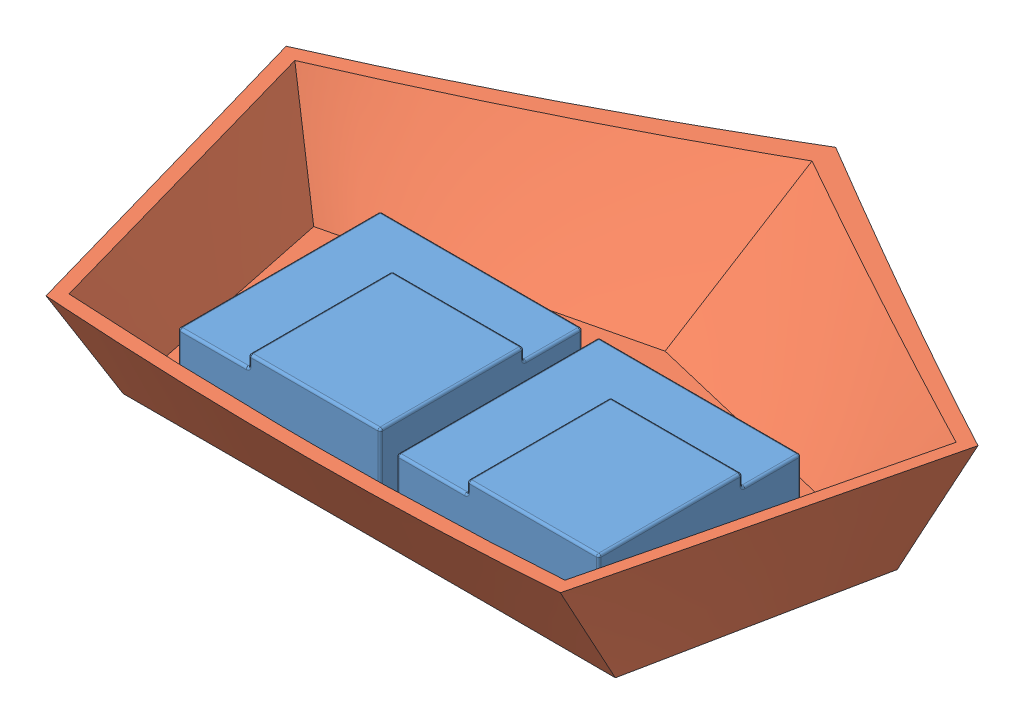
SolidWorks assembly Assem1, configuration Default. Lengths in mm.
Overall size (221.51 39.34 171.36).
3 component instances, 2 part files, 5 mates.
Components (placement in the parent):
- ESC-1: ESC [Default] at (-34.6273 0 30.2757) size (64.77 21.59 64.77)
- ESC housing-1: ESC housing [Default] at origin size (221.51 39.34 171.36)
- ESC-2: ESC [Default] at (35.3361 0 30.2757) size (64.77 21.59 64.77)
Mates (geometry in assembly coordinates):
- Coincident1: coincident aligned: plane of ESC housing-1 through (0 0 0) normal (0 1 0); plane of assembly through (0 0 0) normal (0 1 0)
- Coincident2: coordinate: point of ESC housing-1; point of assembly
- Coincident5: coincident anti-aligned: plane of ESC housing-1 through (0 0 0) normal (0 1 0); plane of ESC-2 through (35.3361 0 30.2757) normal (0 -1 0)
- Coincident6: coincident anti-aligned: plane of ESC-1 through (-34.6273 0 30.2757) normal (0 -1 0); plane of ESC housing-1 through (0 0 0) normal (0 1 0)
- Coincident7: coincident aligned: plane of ESC-1 through (-67.0123 21.59 -2.1093) normal (0 0 -1); plane of ESC-2 through (2.9511 21.59 -2.1093) normal (0 0 -1)
